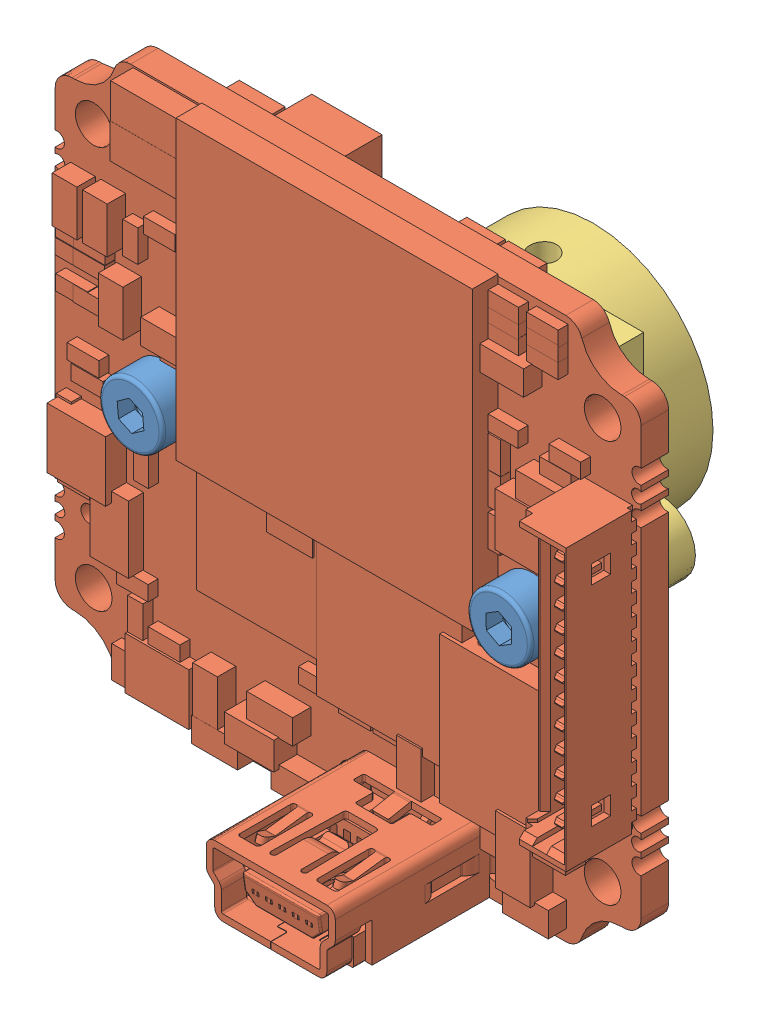
SolidWorks assembly mvBlueFOX-MLC_S-Mount, configuration Standard. Lengths in mm.
Overall size (35 32.52 23.84).
4 component instances, 3 part files, 0 mates.
Components (placement in the parent):
- Socket Head Cap Screw_DIN_DIN 912 M2 x 3 --- 3N-1: Socket Head Cap Screw_DIN_DIN 912 M2 x 3 --- 3N [Standard] at (-11 0 3.6432) x (0 0 -1) z (0.995759 0.091998 0) size (5 3.8 3.8)
- mvBF-MLC-20.04.2010_Default-1: mvBF-MLC-20.04.2010_Default [Standard] at origin size (35 32.52 13.44)
- Socket Head Cap Screw_DIN_DIN 912 M2 x 3 --- 3N-2: Socket Head Cap Screw_DIN_DIN 912 M2 x 3 --- 3N [Standard] at (11 0 3.6432) x (0 0 -1) z (0.999692 0.024825 0) size (5 3.8 3.8)
- Lensation-SH02M13_Default-1: Lensation-SH02M13_Default [Standard] x (0 1 0) z (0 0 -1) size (20 26.2 13)
